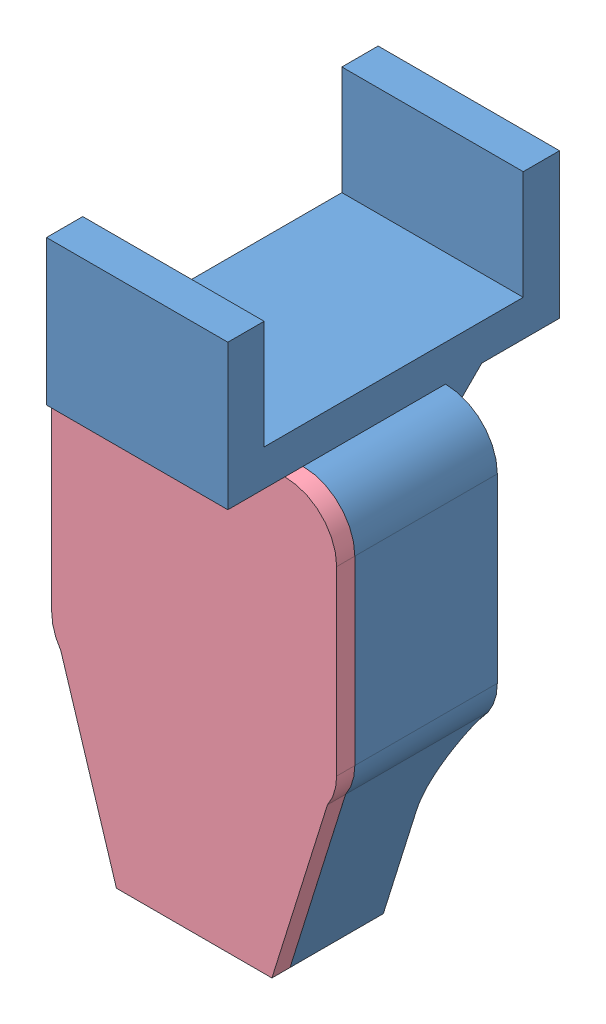
SolidWorks assembly Ensamblaje1, configuration Predeterminado. Lengths in mm.
Overall size (55 113.37 64).
6 component instances, 6 part files, 13 mates.
Components (placement in the parent):
- caja-1: caja [Predeterminado] at (-6.1876 -2.6888 103) size (55 113 64)
- Pieza1-1: Pieza1 [Predeterminado] at (-6.1876 -2.6888 107) x (-0.925052 0.37984 0) z (0 0 -1) size (40 40 23.5)
- piston-1: piston [Predeterminado] at (-6.1876 -25.6865 115.5) size (30 17.38 15)
- tapa-1: tapa [Predeterminado] at (-4.2799 0.5196 130.5) size (55 85 3.5)
- viela-1: viela [Predeterminado] at (-0.3904 -11.8521 115.5) x (-0.38648 -0.922298 0) z (0 0 1) size (45 15 12.5)
- xxx-2: xxx [Predeterminado] at (-6.1876 -38.0616 123) x (1 0 0) z (0 -1 0) size (30 15 22.5)
Mates (geometry in assembly coordinates):
- Coincidente1: coincident anti-aligned: plane of caja-1 through (-23.6876 -20.1888 107) normal (0 0 1); plane of Pieza1-1 through (-6.1876 -2.6888 107) normal (0 0 -1)
- Concéntrica1: concentric aligned: cylinder of caja-1 through (-6.1876 -2.6888 107) axis (0 0 -1) radius 2.5; cylinder of Pieza1-1 through (-6.1876 -2.6888 115.5) axis (0 0 -1) radius 2.45
- Coincidente2: coincident anti-aligned: plane of caja-1 through (11.3124 -20.1888 115.5) normal (0 0 1); plane of piston-1 through (-6.1876 -25.6865 115.5) normal (0 0 -1)
- Coincidente3: coincident anti-aligned: plane of caja-1 through (-21.1876 -2.6888 130.5) normal (1 0 0); plane of piston-1 through (-21.1876 -20.6865 117.5) normal (-1 0 0)
- Concéntrica2: concentric aligned: cylinder of Pieza1-1 through (5.4068 1.9824 130.5) axis (0 0 -1) radius 4.25; cylinder of viela-1 through (5.4068 1.9824 128) axis (0 0 -1) radius 4.25
- Concéntrica3: concentric aligned: cylinder of piston-1 through (-6.1876 -25.6865 130.5) axis (0 0 -1) radius 4.25; cylinder of viela-1 through (-6.1876 -25.6865 128) axis (0 0 -1) radius 4.25
- Coincidente6: coincident anti-aligned: plane of caja-1 through (8.8124 -2.6888 130.5) normal (-1 0 0); plane of xxx-2 through (8.8124 -40.5616 130.5) normal (1 0 0)
- Coincidente7: coincident anti-aligned: plane of caja-1 through (11.3124 -20.1888 115.5) normal (0 0 1); plane of xxx-2 through (-21.1876 -40.5616 115.5) normal (0 0 -1)
- Coincidente8: coincident anti-aligned: plane of piston-1 through (-21.1876 -38.0616 117.5) normal (0 -1 0); plane of xxx-2 through (-6.1876 -38.0616 123) normal (0 1 0)
- Coincidente10: coincident anti-aligned: plane of caja-1 through (11.3124 -20.1888 115.5) normal (0 0 1); plane of viela-1 through (12.0251 -9.0554 115.5) normal (0 0 -1)
- Coincidente11: coincident anti-aligned: plane of caja-1 through (-6.1876 -2.6888 130.5) normal (0 0 1); plane of tapa-1 through (11.3124 14.8112 130.5) normal (0 0 -1)
- Coincidente12: coincident aligned: plane of caja-1 through (21.3124 14.8112 107) normal (1 0 0); plane of tapa-1 through (21.3124 14.8112 134) normal (1 0 0)
- Coincidente13: coincident anti-aligned: plane of caja-1 through (-6.1876 24.8112 103) normal (0 -1 0); plane of tapa-1 through (-23.6876 24.8112 134) normal (0 1 0)
